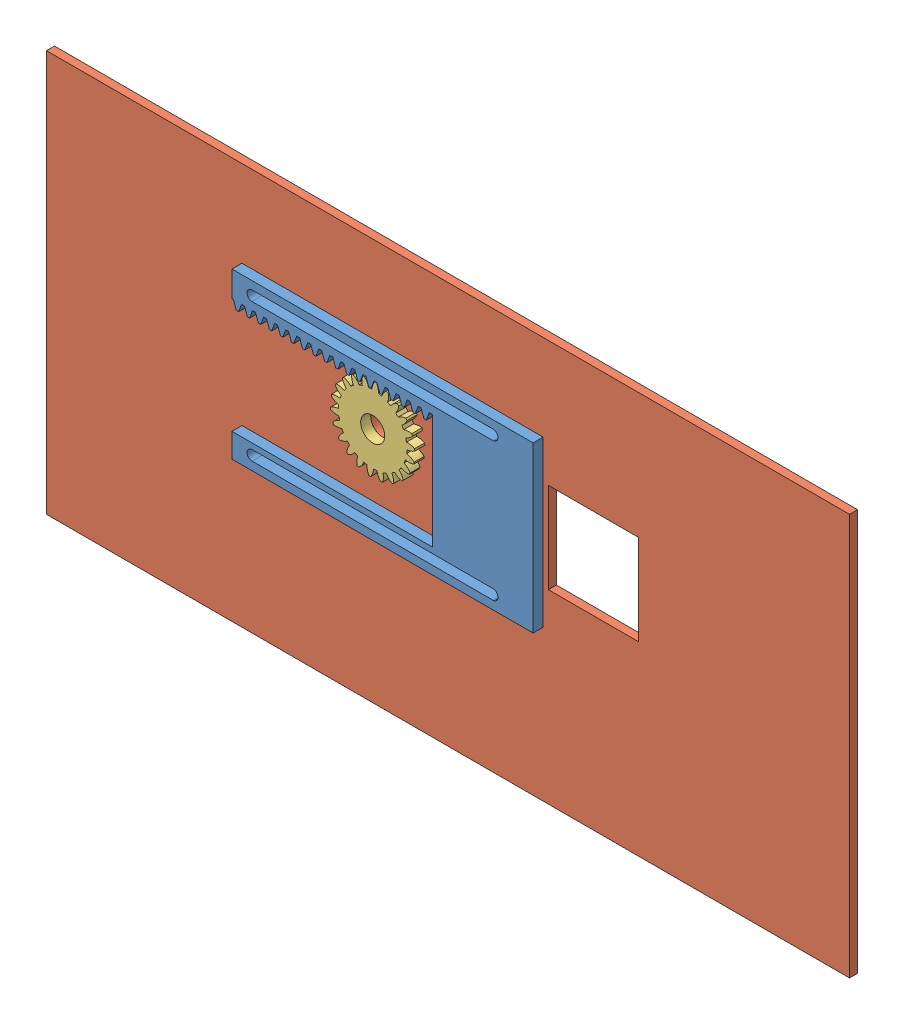
SolidWorks assembly side wall 1, configuration Default. Lengths in mm.
Overall size (400 200 9).
3 component instances, 3 part files, 8 mates.
Components (placement in the parent):
- WINDOW FRAME-1: WINDOW FRAME [Default] at (247.4008 157 4) x (1 0 0) z (0 0 -1) size (150 82 5)
- WINDOW-WALL-1: WINDOW-WALL [Default] at origin size (400 200 4)
- spur gear_amfff-1: spur gear_amfff [Metric - Spur gear 1.75M 22T 20PA 5FW ---S22N75H50L12N] at (167.5 123 4) x (0 0 1) z (0.598973 0.800769 0) size (5 41.7 42)
Mates (geometry in assembly coordinates):
- Coincident1: coincident: plane of assembly through (0 0 0) normal (0 0 1); plane of WINDOW-WALL-1 through (0 0 0) normal (0 0 1)
- Coincident2: coincident: plane of WINDOW-WALL-1 through (0 0 0) normal (0 1 0); plane of assembly through (0 0 0) normal (0 1 0)
- Coincident3: coincident: plane of WINDOW-WALL-1 through (0 0 0) normal (1 0 0); plane of assembly through (0 0 0) normal (1 0 0)
- RackPinionMate3: rack pinion = 38.5 mm: line of WINDOW FRAME-1 through (97.4008 157 9) axis (1 0 0); circle of spur gear_amfff-1
- Distance1: distance = 75 mm: plane of WINDOW FRAME-1 through (247.4008 75 4) normal (0 -1 0); plane of WINDOW-WALL-1 through (400 0 4) normal (0 -1 0)
- Coincident5: coincident: plane of WINDOW FRAME-1 through (247.4008 157 4) normal (0 0 -1); plane of WINDOW-WALL-1 through (0 25 4) normal (0 0 1)
- Coincident6: coincident: plane of WINDOW-WALL-1 through (0 25 4) normal (0 0 1); plane of spur gear_amfff-1 through (167.5 123 4) normal (0 0 -1)
- Concentric1: concentric: cylinder of WINDOW-WALL-1 through (167.5 123 0) axis (0 0 1) radius 6; cylinder of spur gear_amfff-1 through (167.5 123 54.0001) axis (0 0 -1) radius 6
